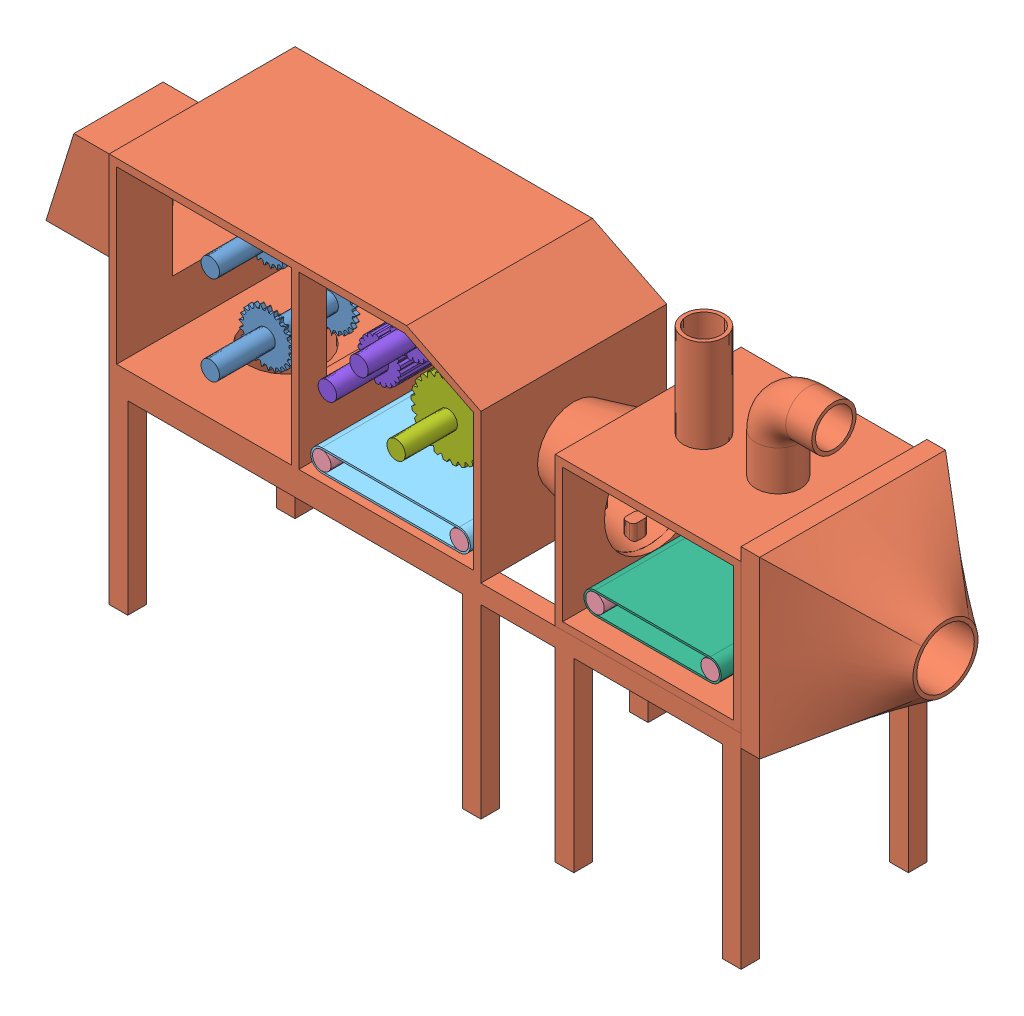
SolidWorks assembly Assem1-in progress, configuration Default. Lengths in mm.
Overall size (2300.01 1200 500).
14 component instances, 8 part files, 23 mates.
Components (placement in the parent):
- blades cutter and shaft-1: blades cutter and shaft [Default] at (567.364 418.6596 -403.61) x (-0.976447 -0.215759 0) z (0 0 -1) size (144.84 144.55 480)
- main frame-1: main frame [Default] at (297.364 288.6596 -901.61) size (2300.01 1200 500)
- blades cutter and shaft-2: blades cutter and shaft [Default] at (567.364 658.6596 -883.61) x (-0.47589 0.879505 0) z (0 0 1) size (144.84 144.55 480)
- pulley shaft-5: pulley shaft [Default] at (133.614 636.4096 -601.61) x (0.7077 0 -0.706513) z (0 -1 0) size (49.75 49.75 199.75)
- pulley shaft-6: pulley shaft [Default] at (133.614 636.4096 -701.61) x (0.7077 0 -0.706513) z (0 -1 0) size (49.75 49.75 199.75)
- conveyor bed shaft-3: conveyor bed shaft [Default] at (857.364 348.6596 -883.61) x (0.787168 0.616738 0) z (0 0 1) size (49.75 49.75 470.02)
- conveyor bed shaft-4: conveyor bed shaft [Default] at (1227.364 348.6596 -883.61) x (0.907562 -0.419919 0) z (0 0 1) size (49.75 49.75 470.02)
- Belt1-1-1: Belt1-1 [Default] at (857.364 348.6596 -648.6) x (-1 0 0) z (0 0 -1) size (429.75 59.75 470)
- conveyor bed shaft-5: conveyor bed shaft [Default] at (1902.364 383.6596 -883.61) x (0.999981 0.006089 0) z (0 0 1) size (49.75 49.75 470.02)
- conveyor bed shaft-6: conveyor bed shaft [Default] at (1592.364 383.6596 -883.61) x (0.999906 -0.013739 0) z (0 0 1) size (49.75 49.75 470.02)
- Belt2-2-1: Belt2-2 [Default] at (1592.364 383.6596 -648.6) x (-1 0 0) z (0 0 -1) size (369.75 59.75 470)
- big cutter shaft-1: big cutter shaft [Default] at (1067.364 483.6596 -883.61) x (0.978239 -0.20748 0) z (0 0 1) size (200.23 199.84 480)
- small cutter shaft-1: small cutter shaft [Default] at (882.364 528.6596 -883.61) x (0.993511 -0.113732 0) z (0 0 1) size (115 115 480)
- small cutter shaft-2: small cutter shaft [Default] at (967.364 628.6596 -883.61) x (0.929634 -0.368485 0) z (0 0 1) size (115 115 480)
Mates (geometry in assembly coordinates):
- Coincident2: coincident anti-aligned: plane of blades cutter and shaft-1 through (567.364 418.6596 -883.61) normal (0 0 -1); plane of main frame-1 through (567.364 418.6596 -883.61) normal (0 0 1)
- Concentric4: concentric aligned: cylinder of blades cutter and shaft-1 through (567.364 418.6596 -883.61) axis (0 0 1) radius 24.875; circle of main frame-1
- Coincident4: coincident anti-aligned: plane of main frame-1 through (567.364 658.6596 -883.61) normal (0 0 1); plane of blades cutter and shaft-2 through (567.364 658.6596 -883.61) normal (0 0 -1)
- Concentric5: concentric aligned: circle of main frame-1; circle of blades cutter and shaft-2
- Coincident5: coincident anti-aligned: plane of main frame-1 through (133.614 436.6596 -601.61) normal (0 1 0); plane of pulley shaft-5 through (133.614 436.6596 -601.61) normal (0 -1 0)
- Concentric6: concentric anti-aligned: circle of main frame-1; circle of pulley shaft-5
- Coincident8: coincident anti-aligned: plane of main frame-1 through (857.364 348.6596 -883.61) normal (0 0 1); plane of conveyor bed shaft-3 through (857.364 348.6596 -883.61) normal (0 0 -1)
- Concentric7: concentric anti-aligned: circle of main frame-1; cylinder of conveyor bed shaft-3 through (857.364 348.6596 -413.59) axis (0 0 -1) radius 24.875
- Coincident11: coincident anti-aligned: plane of main frame-1 through (1227.364 348.6596 -883.61) normal (0 0 1); plane of conveyor bed shaft-4 through (1227.364 348.6596 -883.61) normal (0 0 -1)
- Concentric8: concentric anti-aligned: circle of main frame-1; cylinder of conveyor bed shaft-4 through (1227.364 348.6596 -413.59) axis (0 0 -1) radius 24.875
- BeltMate1: belt = 49.75 : 49.75 mm: cylinder of conveyor bed shaft-3 through (857.364 348.6596 -413.59) axis (0 0 -1) radius 24.875; cylinder of conveyor bed shaft-4 through (1227.364 348.6596 -413.59) axis (0 0 -1) radius 24.875
- Coincident12: coincident anti-aligned: plane of main frame-1 through (1902.364 383.6596 -883.61) normal (0 0 1); plane of conveyor bed shaft-5 through (1902.364 383.6596 -883.61) normal (0 0 -1)
- Concentric9: concentric aligned: circle of main frame-1; circle of conveyor bed shaft-5
- Coincident13: coincident anti-aligned: plane of main frame-1 through (1592.364 383.6596 -883.61) normal (0 0 1); plane of conveyor bed shaft-6 through (1592.364 383.6596 -883.61) normal (0 0 -1)
- Concentric10: concentric aligned: circle of main frame-1; circle of conveyor bed shaft-6
- BeltMate2: belt = 49.75 : 49.75 mm: cylinder of conveyor bed shaft-6 through (1592.364 383.6596 -413.59) axis (0 0 -1) radius 24.875; cylinder of conveyor bed shaft-5 through (1902.364 383.6596 -413.59) axis (0 0 -1) radius 24.875
- LockToSketchMate2: unknown aligned: line of Belt2-2-1 through (1592.364 383.6596 -648.6) axis (-1 0 0); line of Belt2-2-1 through (1592.364 383.6596 -648.6) axis (0 1 0)
- Coincident14: coincident: plane of main frame-1 through (1067.364 483.6596 -883.61) normal (0 0 1); plane of big cutter shaft-1 through (1067.364 483.6596 -883.61) normal (0 0 -1)
- Concentric11: concentric aligned: circle of main frame-1; circle of big cutter shaft-1
- Coincident16: coincident: plane of main frame-1 through (967.364 628.6596 -883.61) normal (0 0 1); plane of small cutter shaft-1 through (882.364 528.6596 -883.61) normal (0 0 -1)
- Concentric12: concentric aligned: circle of main frame-1; circle of small cutter shaft-1
- Coincident17: coincident: plane of main frame-1 through (967.364 628.6596 -883.61) normal (0 0 1); plane of small cutter shaft-2 through (967.364 628.6596 -883.61) normal (0 0 -1)
- Concentric13: concentric aligned: circle of main frame-1; circle of small cutter shaft-2
